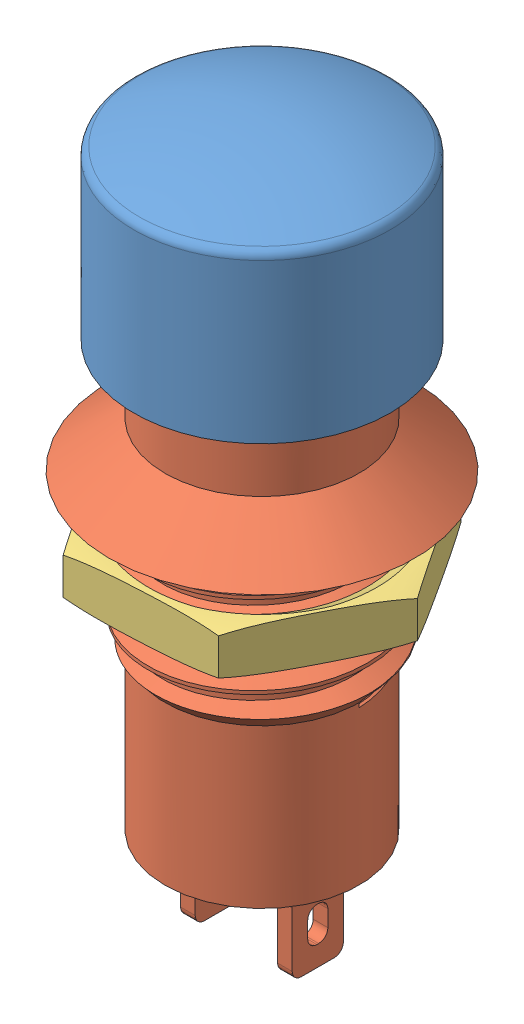
SolidWorks assembly Assem1, configuration Default. Lengths in mm.
Overall size (20.54 38.7 21.18).
3 component instances, 3 part files, 4 mates.
Components (placement in the parent):
- PushBottom_2-1: PushBottom_2 [Default] at (10.7416 7.3599 21.2812) x (-0.98077 0 0.195166) z (-0.195166 0 -0.98077) size (14 10.5 14)
- PushBotton-1: PushBotton [Default] at (10.7416 -15.8401 21.2812) size (16.7 29.5 16.7)
- PushBottom_Screw-1: PushBottom_Screw [Default] at (10.7416 -3.3401 21.2812) x (-0.544892 0 -0.838506) z (0.838506 0 -0.544892) size (16.16 5.04 13.99)
Mates (geometry in assembly coordinates):
- Concentric1: concentric aligned: cylinder of PushBottom_2-1 through (10.7416 7.3599 21.2812) axis (0 -1 0) radius 7; cylinder of PushBotton-1 through (10.7416 -15.8401 21.2812) axis (0 -1 0) radius 5.3
- LimitDistance1: limit distance = 6.2 mm aligned: plane of PushBottom_2-1 through (10.7416 7.3599 21.2812) normal (0 -1 0); plane of PushBotton-1 through (10.7416 1.1599 21.2812) normal (0 -1 0)
- Concentric2: concentric aligned: cylinder of PushBotton-1 through (10.7416 -15.8401 21.2812) axis (0 -1 0) radius 5.3; circle of PushBottom_Screw-1
- Distance2: distance = 2 mm anti-aligned: plane of PushBotton-1 through (10.7416 1.1599 21.2812) normal (0 -1 0); plane of PushBottom_Screw-1 through (7.4722 -0.8401 16.2501) normal (0 1 0)
